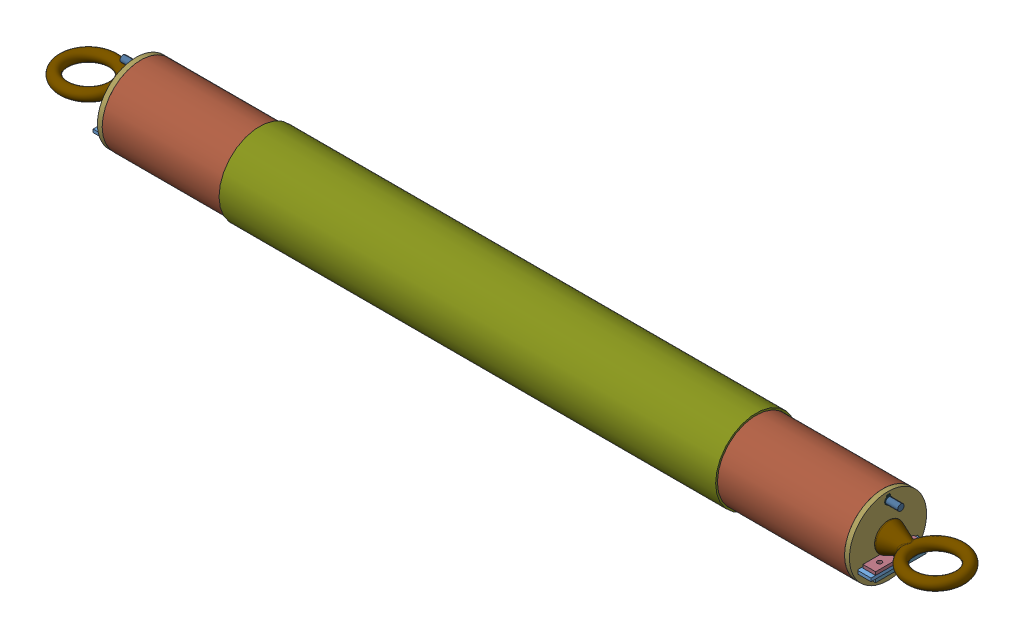
SolidWorks assembly EbayMountedComponents, configuration Default. Lengths in mm.
Overall size (454.72 40.74 40.74).
27 component instances, 18 part files, 56 mates.
Components (placement in the parent):
- EbayComponentBoard-1: EbayComponentBoard [Default] at origin size (389.89 1.59 30)
- AIMXTRA-1: AIMXTRA [Default] at (137.7596 6.35 -15) size (164.92 17.08 30)
- BatterySupport-2: BatterySupport [Default] at (311.15 9.1186 -15) size (6.35 24.93 34.8)
- Batt1S1000mAh-1: Batt1S1000mAh [Default] at (235.7269 1.5875 -2.3893) size (67.95 6.86 24.89)
- Batt2S300mAh-1: Batt2S300mAh [Default] at (230.5587 8.4455 -4.0704) size (38.35 13.46 21.59)
- Batt2S300mAh-2: Batt2S300mAh [Default] at (268.9127 8.4455 -4.0704) size (38.35 13.46 21.59)
- Raven-1: Raven [Default] at (321.1068 6.35 -25.2299) x (0 0 1) z (0 1 0) size (20.32 45.72 6.35)
- ThermBoardScrewTerm-1: ThermBoardScrewTerm [Default] at (191.1096 6.35 -6.11) size (30.48 10.09 17.78)
- EbayMidsectionBottomSwitch-1: EbayMidsectionBottomSwitch [Default] at (190.5 9.1186 -15) size (80.01 38.56 38.56)
- AntennaSupport-1: AntennaSupport [Default] at (47.5996 9.1186 -15) size (6.35 24.93 34.8)
- FiberglassRod1_8in-1: FiberglassRod1_8in [Default] at (0 24.7396 -15) size (389.89 3.17 3.17)
- 6inFiberglassCoupler-1: 6inFiberglassCoupler [Default] at (8.89 9.1186 -15) size (152.4 38.76 38.76)
- 6inFiberglassCoupler-2: 6inFiberglassCoupler [Default] at (228.6 9.1186 -15) size (152.4 38.76 38.76)
- EBayBulkheadWSlots-1: EBayBulkheadWSlots [Default] at (6.477 9.1186 -15) size (5.08 38.66 38.66)
- EBayBulkheadWSlots-2: EBayBulkheadWSlots [Default] at (383.413 9.1186 -15) x (-1 0 0) z (0 0 -1) size (5.08 38.66 38.66)
- ComponentBoardLockPlateThreaded-1: ComponentBoardLockPlateThreaded [Default] at (0 -0.8001 -15) size (6.35 1.6 25.4)
- ComponentBoardLockPlateClearance-1: ComponentBoardLockPlateClearance [Default] at (0 2.3876 -15) size (6.35 1.6 25.4)
- ComponentBoardLockPlateThreaded-2: ComponentBoardLockPlateThreaded [Default] at (383.54 2.3876 -15) size (6.35 1.6 25.4)
- ComponentBoardLockPlateClearance-2: ComponentBoardLockPlateClearance [Default] at (383.54 -0.8001 -15) size (6.35 1.6 25.4)
- 97633A110_EXTERNAL RETAINING RING-1: 97633A110_EXTERNAL RETAINING RING [97633A110] at (383.667 24.7396 -15) size (0.25 5.64 5.64)
- 9p8InThinWallFiberglass-1: 9p8InThinWallFiberglass [Default] at (68.453 9.1186 -15) size (248.92 40.74 40.74)
- 97633A110_EXTERNAL RETAINING RING-2: 97633A110_EXTERNAL RETAINING RING [97633A110] at (6.223 24.7396 -15) size (0.25 5.64 5.64)
- ScrewSwitchFW-1: ScrewSwitchFW [Default] at (210.5406 -1.6002 -23.5725) x (0 0 1) z (1 0 0) size (17.14 6.01 5.84)
- ScrewSwitchFW-2: ScrewSwitchFW [Default] at (204.1906 -1.6002 -23.5725) x (0 0 1) z (1 0 0) size (17.14 6.01 5.84)
- ScrewSwitchFW-3: ScrewSwitchFW [Default] at (216.8906 -1.6002 -23.5725) x (0 0 1) z (1 0 0) size (17.14 6.01 5.84)
- 3014T450_STL EYEBOLT W SHLDR - FOR LIFTING-1: 3014T450_STL EYEBOLT W SHLDR - FOR LIFTING [3014T45] at (407.2255 9.1186 -15) x (0 0.002905 -0.999996) z (0 -0.999996 -0.002905) size (30.16 52.15 14.29)
- 3014T450_STL EYEBOLT W SHLDR - FOR LIFTING-2: 3014T450_STL EYEBOLT W SHLDR - FOR LIFTING [3014T45] at (-17.3355 9.1186 -15) x (0 0.005189 0.999987) z (0 -0.999987 0.005189) size (30.16 52.15 14.29)
Mates (geometry in assembly coordinates):
- Distance1: distance = 4.7625 mm anti-aligned: plane of EbayComponentBoard-1 through (0 1.5875 0) normal (0 1 0); plane of AIMXTRA-1 through (137.7596 6.35 -15) normal (0 -1 0)
- Concentric1: concentric aligned: cylinder of EbayComponentBoard-1 through (90.7596 1.5875 -3) axis (0 1 0) radius 1.4732; cylinder of AIMXTRA-1 through (90.7596 1.716 -3) axis (0 1 0) radius 1.5
- Concentric3: concentric anti-aligned: cylinder of EbayComponentBoard-1 through (314.325 1.5875 -6.11) axis (0 1 0) radius 1.4732; cylinder of BatterySupport-2 through (314.325 1.5875 -6.11) axis (0 -1 0) radius 1.1303
- Coincident3: coincident anti-aligned: plane of EbayComponentBoard-1 through (0 1.5875 0) normal (0 1 0); plane of BatterySupport-2 through (311.15 1.5875 3.2083) normal (0 -1 0)
- Coincident5: coincident anti-aligned: plane of EbayComponentBoard-1 through (0 1.5875 0) normal (0 1 0); plane of Batt1S1000mAh-1 through (235.7269 1.5875 -2.3893) normal (0 -1 0)
- Coincident6: coincident aligned: plane of Batt2S300mAh-1 through (230.5587 21.9075 -4.0704) normal (0 1 0); plane of Batt2S300mAh-2 through (268.9127 21.9075 -4.0704) normal (0 1 0)
- Coincident7: coincident aligned: plane of Batt2S300mAh-1 through (230.5587 21.9075 -4.0704) normal (0 0 1); plane of Batt2S300mAh-2 through (268.9127 21.9075 -4.0704) normal (0 0 1)
- Coincident8: coincident anti-aligned: plane of Batt2S300mAh-1 through (268.9127 21.9075 -4.0704) normal (1 0 0); plane of Batt2S300mAh-2 through (268.9127 21.9075 -4.0704) normal (-1 0 0)
- Coincident9: coincident anti-aligned: plane of Batt1S1000mAh-1 through (235.7269 8.4455 -2.3893) normal (0 1 0); plane of Batt2S300mAh-2 through (268.9127 8.4455 -4.0704) normal (0 -1 0)
- Distance4: distance = 4.7625 mm anti-aligned: plane of EbayComponentBoard-1 through (0 1.5875 0) normal (0 1 0); plane of Raven-1 through (321.1068 6.35 -25.2299) normal (0 -1 0)
- Concentric6: concentric aligned: cylinder of EbayComponentBoard-1 through (331.2668 1.5875 -7.2911) axis (0 1 0) radius 1.1303; cylinder of Raven-1 through (331.2668 7.9375 -7.2911) axis (0 1 0) radius 1.2192
- Parallel1: parallel aligned: cylinder of EbayComponentBoard-1 through (363.7788 1.5875 -22.7089) axis (0 1 0) radius 1.1303; cylinder of Raven-1 through (364.2868 7.9375 -22.8486) axis (0 1 0) radius 1.2192
- Parallel2: parallel aligned: plane of EbayComponentBoard-1 through (0 1.5875 -30) normal (0 0 -1); plane of Raven-1 through (321.1068 7.9375 -25.2299) normal (0 0 -1)
- Distance5: distance = 4.7625 mm anti-aligned: plane of EbayComponentBoard-1 through (0 1.5875 0) normal (0 1 0); plane of ThermBoardScrewTerm-1 through (191.1096 6.35 -6.11) normal (0 -1 0)
- Concentric8: concentric aligned: cylinder of EbayComponentBoard-1 through (193.0146 1.5875 -21.985) axis (0 1 0) radius 1.1303; cylinder of ThermBoardScrewTerm-1 through (193.0146 7.9375 -21.985) axis (0 1 0) radius 1.1303
- Coincident16: coincident anti-aligned: plane of EbayComponentBoard-1 through (0 0 0) normal (0 -1 0); plane of EbayMidsectionBottomSwitch-1 through (190.5 0 0.25) normal (0 1 0)
- Concentric9: concentric aligned: cylinder of EbayComponentBoard-1 through (198.12 1.5875 -27) axis (0 1 0) radius 1.4732; cylinder of EbayMidsectionBottomSwitch-1 through (198.12 0 -27) axis (0 1 0) radius 1.4732
- Coincident17: coincident anti-aligned: plane of EbayComponentBoard-1 through (0 1.5875 0) normal (0 1 0); plane of AntennaSupport-1 through (47.5996 1.5875 3.2083) normal (0 -1 0)
- Concentric10: concentric anti-aligned: cylinder of EbayComponentBoard-1 through (50.7746 1.5875 -23.89) axis (0 1 0) radius 1.4732; cylinder of AntennaSupport-1 through (50.7746 1.5875 -23.89) axis (0 -1 0) radius 1.1303
- Concentric11: concentric anti-aligned: cylinder of EbayMidsectionBottomSwitch-1 through (154.94 24.7396 -15) axis (1 0 0) radius 1.651; cylinder of FiberglassRod1_8in-1 through (389.89 24.7396 -15) axis (-1 0 0) radius 1.5875
- Coincident19: coincident anti-aligned: plane of EbayMidsectionBottomSwitch-1 through (161.29 9.1186 -15) normal (-1 0 0); plane of 6inFiberglassCoupler-1 through (161.29 9.1186 -15) normal (1 0 0)
- Concentric12: concentric aligned: cylinder of EbayMidsectionBottomSwitch-1 through (161.29 9.1186 -15) axis (-1 0 0) radius 17.3355; cylinder of 6inFiberglassCoupler-1 through (161.29 9.1186 -15) axis (-1 0 0) radius 17.5514
- Coincident20: coincident anti-aligned: plane of EbayMidsectionBottomSwitch-1 through (228.6 9.1186 -15) normal (1 0 0); plane of 6inFiberglassCoupler-2 through (228.6 9.1186 -15) normal (-1 0 0)
- Concentric13: concentric aligned: cylinder of EbayMidsectionBottomSwitch-1 through (234.95 9.1186 -15) axis (-1 0 0) radius 17.3355; cylinder of 6inFiberglassCoupler-2 through (381 9.1186 -15) axis (-1 0 0) radius 17.5514
- Coincident21: coincident anti-aligned: plane of 6inFiberglassCoupler-1 through (8.89 9.1186 -15) normal (-1 0 0); plane of EBayBulkheadWSlots-1 through (8.89 9.1186 -15) normal (1 0 0)
- Concentric15: concentric aligned: cylinder of 6inFiberglassCoupler-1 through (161.29 9.1186 -15) axis (-1 0 0) radius 19.3802; cylinder of EBayBulkheadWSlots-1 through (11.557 9.1186 -15) axis (-1 0 0) radius 19.3294
- Coincident22: coincident anti-aligned: plane of 6inFiberglassCoupler-2 through (381 9.1186 -15) normal (1 0 0); plane of EBayBulkheadWSlots-2 through (381 9.1186 -15) normal (-1 0 0)
- Concentric16: concentric anti-aligned: cylinder of 6inFiberglassCoupler-2 through (381 9.1186 -15) axis (-1 0 0) radius 19.3802; cylinder of EBayBulkheadWSlots-2 through (378.333 9.1186 -15) axis (1 0 0) radius 19.3294
- Concentric17: concentric aligned: cylinder of EbayComponentBoard-1 through (386.715 1.5875 -22.5) axis (0 1 0) radius 1.4732; cylinder of ComponentBoardLockPlateClearance-2 through (386.715 0 -22.5) axis (0 1 0) radius 1.4732
- Concentric18: concentric aligned: cylinder of EbayComponentBoard-1 through (386.715 1.5875 -22.5) axis (0 1 0) radius 1.4732; cylinder of ComponentBoardLockPlateThreaded-2 through (386.715 3.1877 -22.5) axis (0 1 0) radius 1.1303
- Coincident23: coincident anti-aligned: plane of EbayComponentBoard-1 through (0 1.5875 0) normal (0 1 0); plane of ComponentBoardLockPlateThreaded-2 through (389.89 1.5875 -2.3) normal (0 -1 0)
- Coincident24: coincident anti-aligned: plane of EbayComponentBoard-1 through (0 0 0) normal (0 -1 0); plane of ComponentBoardLockPlateClearance-2 through (389.89 0 -2.3) normal (0 1 0)
- Concentric20: concentric aligned: cylinder of EbayComponentBoard-1 through (3.175 1.5875 -7.5) axis (0 1 0) radius 1.4732; cylinder of ComponentBoardLockPlateClearance-1 through (3.175 3.1877 -7.5) axis (0 1 0) radius 1.4732
- Concentric22: concentric aligned: cylinder of EbayComponentBoard-1 through (3.175 1.5875 -7.5) axis (0 1 0) radius 1.4732; cylinder of ComponentBoardLockPlateThreaded-1 through (3.175 0 -7.5) axis (0 1 0) radius 1.1303
- Coincident25: coincident anti-aligned: plane of EbayComponentBoard-1 through (0 0 0) normal (0 -1 0); plane of ComponentBoardLockPlateThreaded-1 through (6.35 0 -2.3) normal (0 1 0)
- Coincident26: coincident anti-aligned: plane of EbayComponentBoard-1 through (0 1.5875 0) normal (0 1 0); plane of ComponentBoardLockPlateClearance-1 through (6.35 1.5875 -2.3) normal (0 -1 0)
- Concentric24: concentric aligned: cylinder of FiberglassRod1_8in-1 through (389.89 24.7396 -15) axis (-1 0 0) radius 1.5875; cylinder of 97633A110_EXTERNAL RETAINING RING-1 through (383.794 24.7396 -15) axis (-1 0 0) radius 1.4224
- Coincident31: coincident anti-aligned: plane of FiberglassRod1_8in-1 through (383.54 24.7396 -15) normal (1 0 0); plane of 97633A110_EXTERNAL RETAINING RING-1 through (383.54 24.7396 -15) normal (-1 0 0)
- Distance6: distance = 66.04 mm aligned: plane of EBayBulkheadWSlots-2 through (383.413 9.1186 -15) normal (1 0 0); plane of 9p8InThinWallFiberglass-1 through (317.373 9.1186 -15) normal (1 0 0)
- Concentric25: concentric aligned: cylinder of EbayMidsectionBottomSwitch-1 through (228.6 9.1186 -15) axis (-1 0 0) radius 19.2786; cylinder of 9p8InThinWallFiberglass-1 through (317.373 9.1186 -15) axis (-1 0 0) radius 20.3708
- Coincident32: coincident aligned: plane of EbayComponentBoard-1 through (389.89 1.5875 0) normal (1 0 0); plane of FiberglassRod1_8in-1 through (389.89 24.7396 -15) normal (1 0 0)
- Concentric26: concentric aligned: cylinder of FiberglassRod1_8in-1 through (389.89 24.7396 -15) axis (-1 0 0) radius 1.5875; cylinder of 97633A110_EXTERNAL RETAINING RING-2 through (6.35 24.7396 -15) axis (-1 0 0) radius 1.4224
- Coincident33: coincident anti-aligned: plane of FiberglassRod1_8in-1 through (6.35 24.7396 -15) normal (-1 0 0); plane of 97633A110_EXTERNAL RETAINING RING-2 through (6.35 24.7396 -15) normal (1 0 0)
- Distance7: distance = 1.6002 mm anti-aligned: plane of EbayComponentBoard-1 through (0 0 0) normal (0 -1 0); plane of ScrewSwitchFW-3 through (216.8906 -1.6002 -23.5725) normal (0 1 0)
- Distance8: distance = 1.6002 mm anti-aligned: plane of EbayComponentBoard-1 through (0 0 0) normal (0 -1 0); plane of ScrewSwitchFW-2 through (204.1906 -1.6002 -23.5725) normal (0 1 0)
- Distance10: distance = 1.6002 mm anti-aligned: plane of EbayComponentBoard-1 through (0 0 0) normal (0 -1 0); plane of ScrewSwitchFW-1 through (210.5406 -1.6002 -23.5725) normal (0 1 0)
- Concentric27: concentric anti-aligned: cylinder of EbayComponentBoard-1 through (201.2696 1.5875 -20.588) axis (0 1 0) radius 1.4732; cylinder of ScrewSwitchFW-2 through (201.2696 -1.6002 -20.588) axis (0 -1 0) radius 1.3462
- Concentric28: concentric anti-aligned: cylinder of EbayComponentBoard-1 through (201.2696 1.5875 -9.412) axis (0 1 0) radius 1.4732; cylinder of ScrewSwitchFW-2 through (201.2696 -1.6002 -9.412) axis (0 -1 0) radius 1.3462
- Concentric29: concentric anti-aligned: cylinder of EbayComponentBoard-1 through (207.6196 1.5875 -20.588) axis (0 1 0) radius 1.4732; cylinder of ScrewSwitchFW-1 through (207.6196 -1.6002 -20.588) axis (0 -1 0) radius 1.3462
- Concentric30: concentric anti-aligned: cylinder of EbayComponentBoard-1 through (207.6196 1.5875 -9.412) axis (0 1 0) radius 1.4732; cylinder of ScrewSwitchFW-1 through (207.6196 -1.6002 -9.412) axis (0 -1 0) radius 1.3462
- Concentric31: concentric anti-aligned: cylinder of EbayComponentBoard-1 through (213.9696 1.5875 -20.588) axis (0 1 0) radius 1.4732; cylinder of ScrewSwitchFW-3 through (213.9696 -1.6002 -20.588) axis (0 -1 0) radius 1.3462
- Concentric32: concentric anti-aligned: cylinder of EbayComponentBoard-1 through (213.9696 1.5875 -9.412) axis (0 1 0) radius 1.4732; cylinder of ScrewSwitchFW-3 through (213.9696 -1.6002 -9.412) axis (0 -1 0) radius 1.3462
- Concentric34: concentric anti-aligned: cylinder of EBayBulkheadWSlots-2 through (383.413 9.1186 -15) axis (-1 0 0) radius 3.175; cone of 3014T450_STL EYEBOLT W SHLDR - FOR LIFTING-1 through (394.9224 9.1186 -15) axis (1 0 0)
- Coincident39: coincident anti-aligned: plane of EBayBulkheadWSlots-2 through (383.413 9.1186 -15) normal (1 0 0); plane of 3014T450_STL EYEBOLT W SHLDR - FOR LIFTING-1 through (383.413 9.0999 -8.5508) normal (-1 0 0)
- Concentric35: concentric anti-aligned: cylinder of EBayBulkheadWSlots-1 through (6.477 9.1186 -15) axis (1 0 0) radius 3.175; cone of 3014T450_STL EYEBOLT W SHLDR - FOR LIFTING-2 through (-5.0324 9.1186 -15) axis (-1 0 0)
- Coincident40: coincident anti-aligned: plane of EBayBulkheadWSlots-1 through (6.477 9.1186 -15) normal (-1 0 0); plane of 3014T450_STL EYEBOLT W SHLDR - FOR LIFTING-2 through (6.477 9.0851 -21.4491) normal (1 0 0)
